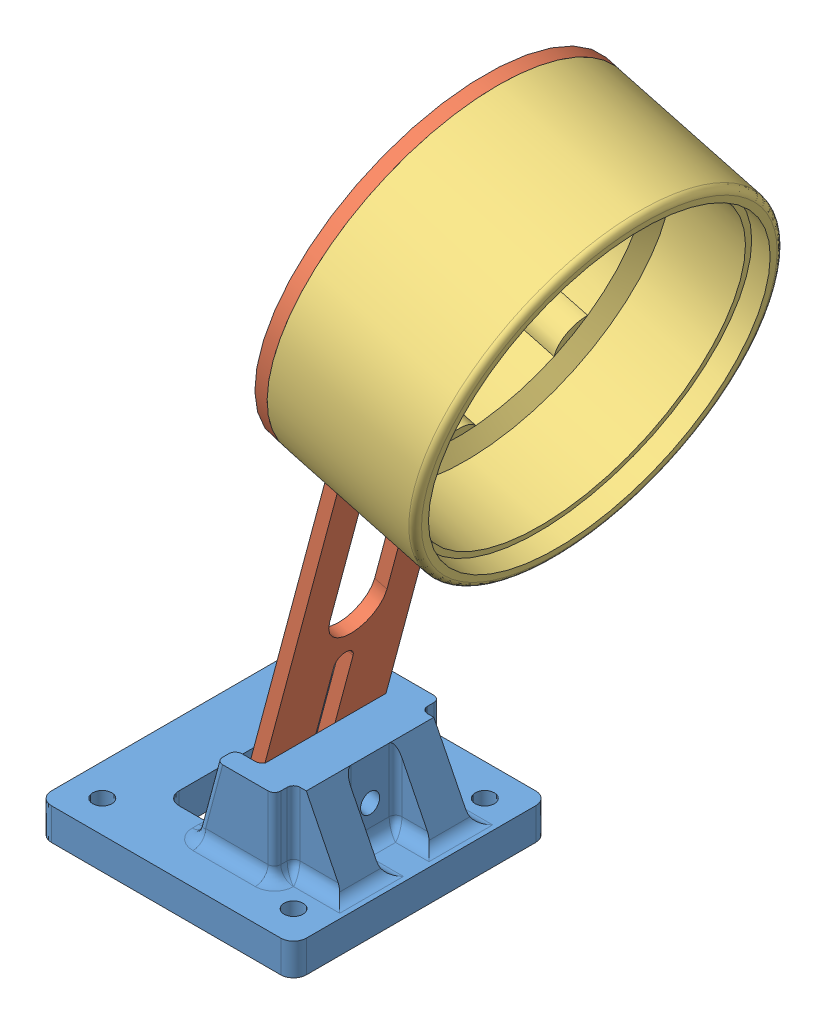
SolidWorks assembly Assemblage1, configuration Défaut. Lengths in mm.
Overall size (75.21 130.43 56).
3 component instances, 3 part files, 6 mates.
Components (placement in the parent):
- SupportCamera-1: SupportCamera [Défaut] at (-33.399 6.1572 0) size (40 17 40)
- support_camera_2-1: support_camera_2 [Défaut] at (-38.1166 -5.3821 0) x (0 0 -1) z (0.965926 -0.258819 0) size (56 134.5 2)
- Casquette-1: Casquette [Défaut] at (-8.6205 96.9713 0) x (0 0 -1) z (0.965926 -0.258819 0) size (56 56 24)
Mates (geometry in assembly coordinates):
- Coïncidente1: coincident anti-aligned: plane of SupportCamera-1 through (-28.399 23.1572 10) normal (-0.965926 0.258819 0); plane of support_camera_2-1 through (-8.6205 96.9713 0) normal (0.965926 -0.258819 0)
- Parallèle1: parallel anti-aligned: plane of SupportCamera-1 through (-33.399 6.1572 10) normal (0 0 -1); plane of support_camera_2-1 through (-15.4376 71.5297 9.5) normal (0 0 1)
- Tangent1: tangent anti-aligned: cylinder of SupportCamera-1 through (-19.9302 16.1261 0) axis (-0.965926 0.258819 0) radius 1.5; plane of support_camera_2-1 through (-27.505 34.2208 -1.5) normal (0 0 1)
- Coïncidente3: coincident anti-aligned: plane of support_camera_2-1 through (-8.6205 96.9713 0) normal (0.965926 -0.258819 0); plane of Casquette-1 through (-8.6205 96.9713 0) normal (-0.965926 0.258819 0)
- Coïncidente4: coincident aligned: circle of support_camera_2-1; circle of Casquette-1
- Coaxiale1: concentric aligned: circle of support_camera_2-1; circle of Casquette-1
